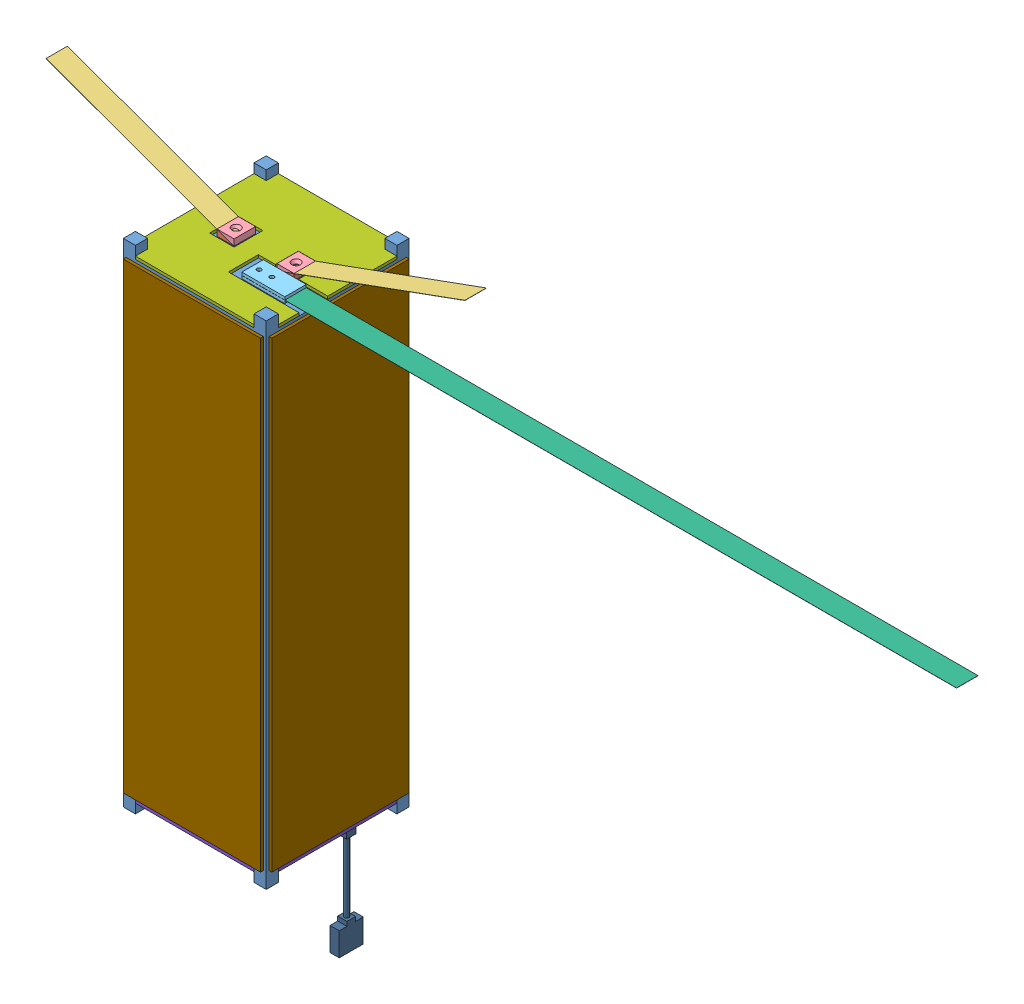
SolidWorks assembly lowfi, configuration Default. Lengths in mm.
Overall size (654.06 457.98 104).
21 component instances, 10 part files, 30 mates.
Components (placement in the parent):
- main-1: main [Default] at (58.2257 18.2154 321.7363) size (100 344.5 100)
- Assem3^lowfi-1: Assem3^lowfi [Default] at (0 67.1368 543.4726) x (1 0 0) z (0 0 -1) size (131.59 47.98 15) (virtual)
  - Dipole Antenna Mount Bottom-1: Dipole Antenna Mount Bottom [Default] at (105.666 51.1847 252.6863) x (-1 0 0) z (0 0 1) size (12 4.37 15)
  - Dipole Deployed-1: Dipole Deployed [Default] at (26.0546 24.3667 255.1165) x (-0.939693 -0.34202 0) z (-0.34202 0.939693 0) size (140 15 0.1)
  - Dipole Antenna Mount Top-1: Dipole Antenna Mount Top [Default] at (68.6539 42.1274 252.6863) size (12 4.37 15)
- Assem2^lowfi-1: Assem2^lowfi [Default] at (0 57.3793 543.4726) x (1 0 0) z (0 0 -1) size (131.59 47.98 15) (virtual)
  - Dipole Antenna Mount Bottom-1: Dipole Antenna Mount Bottom [Default] at (110.7854 41.4271 290.7863) x (1 0 0) z (0 0 -1) size (12 4.37 15)
  - Dipole Deployed-1: Dipole Deployed [Default] at (190.431 14.7031 255.1165) x (0.939693 -0.34202 0) z (-0.34202 -0.939693 0) size (140 15 0.1)
  - Dipole Antenna Mount Top-1: Dipole Antenna Mount Top [Default] at (147.7975 32.3698 290.7863) x (-1 0 0) z (0 0 -1) size (12 4.37 15)
- Assem4^lowfi-1: Assem4^lowfi [Default] at (261.3174 70.1276 9.7408) x (-1 0 0) z (0 0 1) size (500 4.1 15) (virtual)
  - Mono Antenna Mount Bottom-1: Mono Antenna Mount Bottom [Default] at (92.7914 51.3522 298.0455) x (0 0 -1) z (0 -1 0) size (15 30 2)
  - Mono Antenna Mount Bottom-2: Mono Antenna Mount Bottom [Default] at (92.7914 48.3722 259.9455) x (0 0 1) z (0 1 0) size (15 30 2)
  - Monopole Deployed-1: Monopole Deployed [Default] at (74.0733 49.9122 295.6153) x (-1 0 0) z (0 -1 0) size (500 15 0.1)
- top panel1-1: top panel1 [Default] at (0 20.2154 0) x (-1 0 0) z (0 -1 0) size (100 100 2)
- Assem5^lowfi-1: Assem5^lowfi [Default] at (-67.4589 8.8134 227.6523) x (0 0 -1) z (1 0 0) size (100 2 100) (virtual)
  - bottom panel-1: bottom panel [Default] at (-93.084 -320.0979 126.6846) x (-1 0 0) z (0 1 0) size (100 100 2)
- side panel-1: side panel [Default] at (58.2257 18.2154 323.7363) x (1 0 0) z (0 1 0) size (96 2 323.5)
- side panel-2: side panel [Default] at (58.2257 -309.2846 221.7363) x (0 0 1) z (0 -1 0) size (96 2 323.5)
- side panel-3: side panel [Default] at (158.2257 18.2154 221.7363) x (0 0 1) z (0 1 0) size (96 2 323.5)
- side panel-4: side panel [Default] at (58.2257 18.2154 221.7363) x (1 0 0) z (0 1 0) size (96 2 323.5)
- mag-1: mag [Default] at (144.7257 -349.5346 271.8134) x (0 0 -1) z (1 0 0) size (16.8 82.5 6.5)
Mates (geometry in assembly coordinates):
- Concentric13: concentric anti-aligned: cylinder of main-1 through (129.2257 8.2154 271.7363) axis (0 -1 0) radius 1.2; cylinder of Assem2^lowfi-1/Dipole Antenna Mount Bottom-1 through (129.2257 18.2154 271.7363) axis (0 1 0) radius 1.5
- Coincident55: coincident anti-aligned: plane of main-1 through (58.2257 18.2154 321.7363) normal (0 1 0); plane of Assem2^lowfi-1/Dipole Antenna Mount Bottom-1 through (123.2257 18.2154 279.2363) normal (0 -1 0)
- Concentric14: concentric anti-aligned: cylinder of main-1 through (87.2257 8.2154 271.7363) axis (0 -1 0) radius 1.2; cylinder of Assem3^lowfi-1/Dipole Antenna Mount Bottom-1 through (87.2257 18.2154 271.7363) axis (0 1 0) radius 1.5
- Coincident57: coincident anti-aligned: plane of main-1 through (58.2257 18.2154 321.7363) normal (0 1 0); plane of Assem3^lowfi-1/Dipole Antenna Mount Bottom-1 through (93.2257 18.2154 264.2363) normal (0 -1 0)
- Parallel9: parallel aligned: line of main-1 through (58.2257 18.2154 313.2363) axis (0 0 -1); line of Assem3^lowfi-1/Dipole Antenna Mount Bottom-1 through (81.2257 18.2154 279.2363) axis (0 0 -1)
- Parallel10: parallel anti-aligned: line of main-1 through (158.2257 18.2154 313.2363) axis (0 0 -1); line of Assem2^lowfi-1/Dipole Antenna Mount Bottom-1 through (135.2257 18.2154 264.2363) axis (0 0 1)
- Coincident61: coincident anti-aligned: plane of main-1 through (58.2257 18.2154 321.7363) normal (0 1 0); plane of Assem4^lowfi-1/Mono Antenna Mount Bottom-2 through (145.7257 18.2154 281.2363) normal (0 -1 0)
- Concentric15: concentric anti-aligned: cylinder of main-1 through (120.2257 8.2154 288.7363) axis (0 1 0) radius 1.2; cylinder of Assem4^lowfi-1/Mono Antenna Mount Bottom-1 through (120.2257 22.3154 288.7363) axis (0 -1 0) radius 1.5
- Concentric16: concentric anti-aligned: cylinder of main-1 through (129.2257 8.2154 288.7363) axis (0 1 0) radius 1.2; cylinder of Assem4^lowfi-1/Mono Antenna Mount Bottom-1 through (129.2257 22.3154 288.7363) axis (0 -1 0) radius 1.5
- Coincident63: coincident anti-aligned: plane of main-1 through (58.2257 18.2154 321.7363) normal (0 1 0); plane of top panel1-1 through (0 18.2154 0) normal (0 -1 0)
- Coincident64: coincident aligned: plane of main-1 through (58.2257 -309.2846 321.7363) normal (0 0 1); plane of top panel1-1 through (149.7257 18.2154 321.7363) normal (0 0 1)
- Coincident65: coincident aligned: plane of main-1 through (58.2257 -309.2846 321.7363) normal (-1 0 0); plane of top panel1-1 through (58.2257 18.2154 313.2363) normal (-1 0 0)
- Coincident66: coincident anti-aligned: plane of main-1 through (58.2257 -309.2846 321.7363) normal (0 -1 0); plane of Assem5^lowfi-1/bottom panel-1 through (59.2257 -309.2846 320.7363) normal (0 1 0)
- Coincident67: coincident aligned: plane of main-1 through (58.2257 -309.2846 221.7363) normal (0 0 -1); plane of Assem5^lowfi-1/bottom panel-1 through (149.7257 -309.2846 221.7363) normal (0 0 -1)
- Coincident69: coincident aligned: plane of main-1 through (58.2257 -309.2846 321.7363) normal (-1 0 0); plane of Assem5^lowfi-1/bottom panel-1 through (58.2257 -309.2846 230.2363) normal (-1 0 0)
- Coincident70: coincident anti-aligned: plane of main-1 through (158.2257 -309.2846 321.7363) normal (1 0 0); plane of side panel-3 through (158.2257 18.2154 221.7363) normal (-1 0 0)
- Coincident71: coincident anti-aligned: plane of main-1 through (58.2257 -309.2846 221.7363) normal (0 0 -1); plane of side panel-4 through (58.2257 18.2154 221.7363) normal (0 0 1)
- Coincident73: coincident anti-aligned: plane of main-1 through (58.2257 -309.2846 321.7363) normal (-1 0 0); plane of side panel-2 through (58.2257 -309.2846 221.7363) normal (1 0 0)
- Coincident74: coincident anti-aligned: plane of main-1 through (58.2257 -309.2846 321.7363) normal (0 0 1); plane of side panel-1 through (58.2257 18.2154 321.7363) normal (0 0 -1)
- Distance16: distance = 2 mm aligned: plane of side panel-1 through (60.2257 16.2154 321.7363) normal (-1 0 0); plane of main-1 through (58.2257 -309.2846 321.7363) normal (-1 0 0)
- Distance17: distance = 2 mm: plane of side panel-1 through (60.2257 16.2154 321.7363) normal (0 1 0); line of top panel1-1 through (149.7257 18.2154 321.7363) axis (-1 0 0)
- Distance18: distance = 2 mm: plane of side panel-3 through (160.2257 16.2154 223.7363) normal (0 1 0); line of main-1 through (158.2257 18.2154 313.2363) axis (0 0 -1)
- Distance19: distance = 2 mm aligned: plane of side panel-3 through (160.2257 16.2154 223.7363) normal (0 0 -1); plane of main-1 through (58.2257 -309.2846 221.7363) normal (0 0 -1)
- Distance20: distance = 2 mm aligned: plane of side panel-4 through (156.2257 16.2154 219.7363) normal (1 0 0); plane of main-1 through (158.2257 -309.2846 321.7363) normal (1 0 0)
- Distance21: distance = 2 mm: plane of side panel-4 through (60.2257 16.2154 219.7363) normal (0 1 0); line of top panel1-1 through (66.7257 18.2154 221.7363) axis (1 0 0)
- Distance22: distance = 2 mm aligned: plane of side panel-2 through (56.2257 -307.2846 223.7363) normal (0 0 -1); plane of main-1 through (58.2257 -309.2846 221.7363) normal (0 0 -1)
- Distance23: distance = 2 mm: plane of side panel-2 through (56.2257 16.2154 223.7363) normal (0 1 0); line of top panel1-1 through (58.2257 18.2154 313.2363) axis (0 0 -1)
- Coincident75: coincident anti-aligned: plane of main-1 through (58.2257 -309.2846 321.7363) normal (0 -1 0); plane of mag-1 through (151.2257 -309.2846 247.7363) normal (0 1 0)
- Distance24: distance = 3 mm anti-aligned: plane of mag-1 through (151.2257 -349.5346 271.8134) normal (1 0 0); plane of Assem5^lowfi-1/bottom panel-1 through (154.2257 -309.2846 265.7363) normal (-1 0 0)
- Distance25: distance = 4 mm anti-aligned: plane of mag-1 through (151.2257 -313.7846 247.7363) normal (0 0 -1); plane of Assem5^lowfi-1/bottom panel-1 through (154.2257 -309.2846 243.7363) normal (0 0 1)
